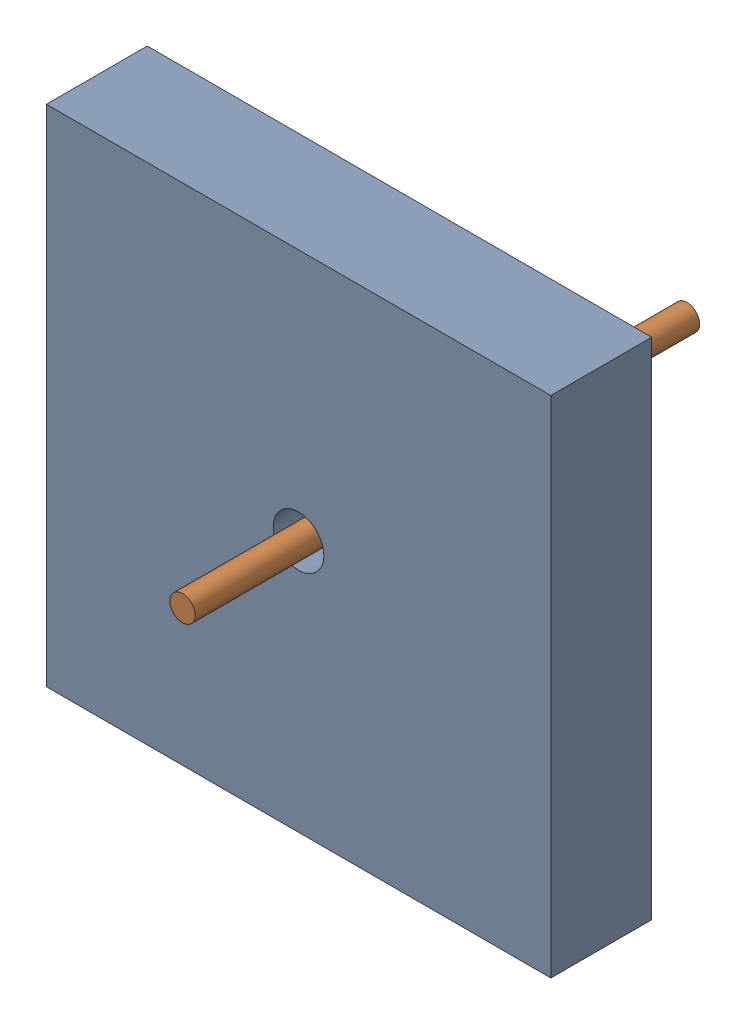
SolidWorks assembly Assem1, configuration ﾃﾞﾌｫﾙﾄ. Lengths in mm.
Overall size (10 10 10).
2 component instances, 2 part files, 1 mates.
Components (placement in the parent):
- base-1: base [ﾃﾞﾌｫﾙﾄ] at (3.0632 -2.1704 0) size (10 10 2)
- cylinder-1: cylinder [ﾃﾞﾌｫﾙﾄ] at (3.0632 -2.1704 -5.6987) size (0.5 0.5 10)
Mates (geometry in assembly coordinates):
- 同心円1: concentric aligned: cylinder of base-1 through (3.0632 -2.1704 2) axis (0 0 -1) radius 0.5; cylinder of cylinder-1 through (3.0632 -2.1704 4.3013) axis (0 0 -1) radius 0.25
